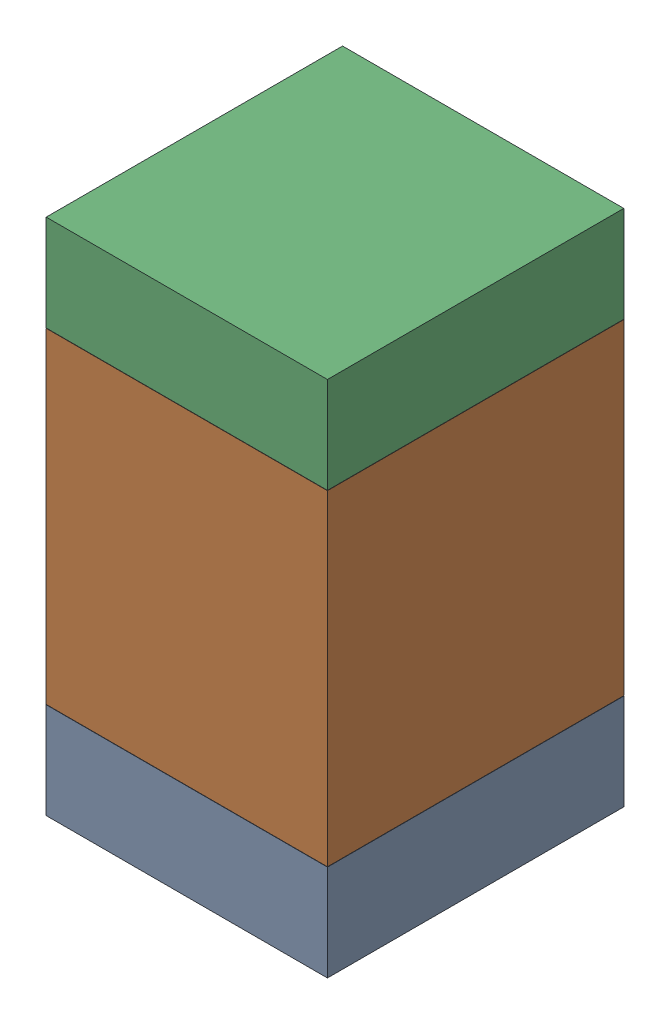
SolidWorks assembly R22, configuration Default. Lengths in mm.
Overall size (0.95 1.75 1).
6 component instances, 2 part files, 0 mates.
Components (placement in the parent):
- 6575495072-1: 6575495072 [Default] at (18.415 11.4795 0) size (0.95 0.32 1)
  - Extruded_6-1: Extruded_6 [Default] at origin size (0.95 0.32 1)
- 6575494912-1: 6575494912 [Default] at (18.415 12.192 0) size (0.95 1.1 1)
  - Extruded_7-1: Extruded_7 [Default] at origin size (0.95 1.1 1)
- 6575495072-2: 6575495072 [Default] at (18.415 12.9045 0) size (0.95 0.32 1)
  - Extruded_6-1: Extruded_6 [Default] at origin size (0.95 0.32 1)
